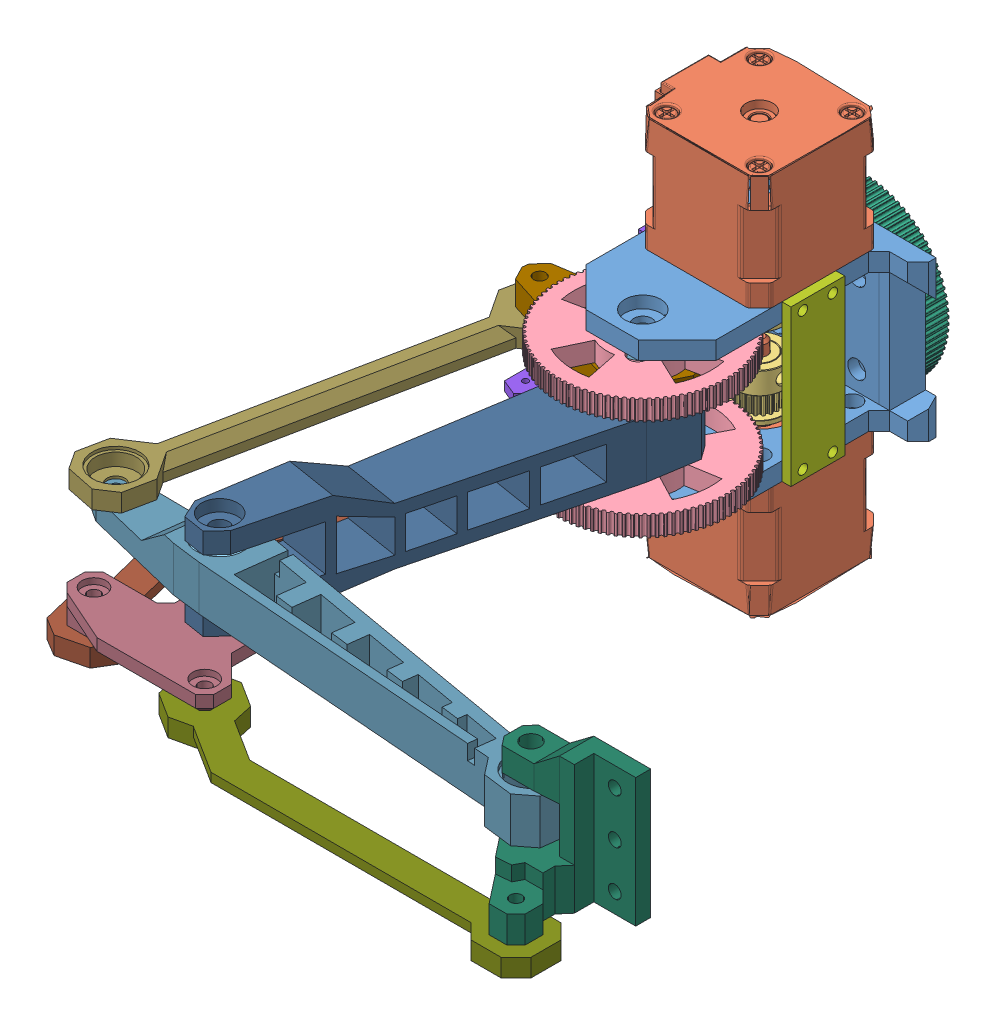
SolidWorks assembly 大臂, configuration 默认. Lengths in mm.
26 component instances, 16 part files, 62 mates.
Components (placement in the parent):
- 支架-1: 支架 [默认] at origin size (71 52.09 83.05)
- 基座电机-1: 基座电机 [默认] at (39 -47.8051 -25.5051) x (1 0 0) z (0 1 0) size (51.25 48 66.15)
- 基座电机-2: 基座电机 [默认] at (39.002 -50.2051 72.5031) x (1 0 0) z (0 -1 0) size (51.25 48 66.15)
- 基座小带轮-1: 基座小带轮 [默认] at (177.9873 -24.2051 17.4258) x (-0.72855 0 0.684993) z (0 1 0) size (16 16 16)
- 基座小带轮-2: 基座小带轮 [默认] at (36.8527 -73.8051 69.7017) x (0.998983 0 0.045086) z (0 -1 0) size (16 16 16)
- 机械臂大带轮-1: 机械臂大带轮 [默认] at (-17.6564 -0.0051 70.6178) x (0.809503 0 -0.587116) z (0.587116 0 0.809503) size (56.79 6.5 56.81)
- 机械臂大带轮轴承-1: 机械臂大带轮轴承 [默认] at (28.3216 -7.0051 156.1487) x (0.094466 0 -0.995528) z (0.995528 0 0.094466) size (15 5 15)
- 机械臂大带轮-2: 机械臂大带轮 [默认] at (140.2401 -98.0051 -48.3425) x (-0.787618 0 0.616164) z (0.616164 0 0.787618) size (56.79 6.5 56.81)
- 机械臂大带轮轴承-2: 机械臂大带轮轴承 [默认] at (217.8896 -91.5051 64.8714) x (-0.837169 0 -0.546944) z (-0.546944 0 0.837169) size (15 5 15)
- 基座大带轮-1: 基座大带轮 [默认] at (-0.0113 -0.0051 0) size (56.79 56.81 10)
- 支架横板-1: 支架横板 [默认] at origin size (3 52 18)
- 支架挡板-1: 支架挡板 [默认] at origin size (14 52 50.36)
- 大臂连杆-1: 大臂连杆 [默认] at (-14.6303 -0.0051 35.9323) x (0.945311 0 -0.32617) z (0.32617 0 0.945311) size (55.83 8 37.89)
- 大臂杆2-1: 大臂杆2 [默认] at (-17.6563 -0.0051 70.618) x (0.809502 0 -0.587118) z (0.587118 0 0.809502) size (110.73 30.5 103.66)
- 机械臂大带轮轴承-3: 机械臂大带轮轴承 [默认] at (-0.0113 -0.0051 0) size (15 5 15)
- 机械臂大带轮轴承-4: 机械臂大带轮轴承 [默认] at (217.8896 -106.0051 64.8714) x (-0.837169 0 -0.546944) z (-0.546944 0 0.837169) size (15 5 15)
- 大臂杆3-1: 大臂杆3 [默认] at (-30.4167 -0.0051 55.2903) x (0.809502 0 -0.587117) z (0.587117 0 0.809502) size (110.51 6 103.44)
- 机械臂大带轮轴承-5: 机械臂大带轮轴承 [默认] at (25.5912 -19.0051 -34.748) x (0.810265 0 0.586064) z (-0.586064 0 0.810265) size (15 5 15)
- 大臂杆1-1: 大臂杆1 [默认] at (-17.6672 -0.0051 58.6826) x (0.810062 0 -0.586344) z (0.586344 0 0.810062) size (109.93 6 102.62)
- 机械臂大带轮轴承-6: 机械臂大带轮轴承 [默认] at (-48.6211 12.4949 13.0424) x (0.985319 0 -0.170721) z (0.170721 0 0.985319) size (15 5 15)
- 三连杆-1: 三连杆 [默认] at (64.5133 -0.0051 36.3743) x (1 0 0.000008) z (-0.000008 0 1) size (57 9.5 36)
- 小臂杆2-1: 小臂杆2 [默认] at (18.7808 -0.1051 47.8224) x (0.946574 0 -0.322488) z (0.322488 0 0.946574) size (161.69 15 86.71)
- 机械臂大带轮轴承-7: 机械臂大带轮轴承 [默认] at (-23.8027 5.3949 117.6181) size (15 5 15)
- 机械臂大带轮轴承-8: 机械臂大带轮轴承 [默认] at (194.0983 -104.6051 182.4895) x (-0.837169 0 -0.546944) z (-0.546944 0 0.837169) size (15 5 15)
- 小臂连杆-1: 小臂连杆 [默认] at (75.7157 -0.0051 -1.219) x (1 0 0.000008) z (-0.000008 0 1) size (40 43 32)
- 小臂杆1-1: 小臂杆1 [默认] at (13.1016 -0.0051 53.7449) x (0.946506 0 -0.322686) z (0.322686 0 0.946506) size (129.85 6 74.64)
Mates (geometry in assembly coordinates):
- 重合1: coincident: plane of ? through (119.9887 -75.0051 -26.5) normal (0 -1 0); plane of 基座电机-1 through (99.9867 -75.0051 23.498) normal (0 1 0)
- 同心1: concentric: cylinder of ? through (115.4887 -75.0051 39) axis (0 1 0) radius 1.65; cylinder of 基座电机-1 through (115.4887 -72.5051 39) axis (0 -1 0) radius 1.25
- 平行2: parallel: plane of ? through (77.4887 -75.0051 47.75) normal (-1 0 0); plane of 基座电机-1 through (78.9867 -103.5051 29.298) normal (-1 0 0)
- 重合3: coincident: plane of ? through (119.9887 -23.0051 -26.5) normal (0 1 0); plane of 基座电机-2 through (99.9887 -23.0051 23.5) normal (0 -1 0)
- 同心4: concentric: cylinder of ? through (99.9887 -28.0051 23.5) axis (0 1 0) radius 11.5; cylinder of 基座电机-2 through (99.9887 -25.5051 23.5) axis (0 -1 0) radius 11
- 平行3: parallel: plane of ? through (77.4887 -28.0051 47.75) normal (-1 0 0); plane of 基座电机-2 through (78.9887 5.4949 17.7) normal (-1 0 0)
- 同心5: concentric: cylinder of assembly; cylinder of assembly; cylinder of 基座电机-2 through (99.9887 -25.5051 23.5) axis (0 -1 0) radius 2.5; cylinder of 基座小带轮-1 through (99.9887 -29.0051 23.5) axis (0 1 0) radius 2.5
- 重合7: coincident: plane of ? through (119.9887 -29.0051 -26.5) normal (0 -1 0); plane of 基座小带轮-1 through (99.9887 -29.0051 23.5) normal (0 -1 0)
- 同心6: concentric: cylinder of assembly; cylinder of assembly; cylinder of 基座电机-1 through (99.9867 -72.5051 23.498) axis (0 1 0) radius 2.5; cylinder of 基座小带轮-2 through (99.9867 -69.0051 23.498) axis (0 -1 0) radius 2.5
- 重合8: coincident: plane of ? through (119.9887 -69.0051 -26.5) normal (0 1 0); plane of 基座小带轮-2 through (99.9867 -69.0051 23.498) normal (0 1 0)
- 重合9: coincident: plane of ? through (119.9887 -69.0051 -26.5) normal (0 1 0); plane of 机械臂大带轮-1 through (-67.6057 -69.0051 35.8138) normal (0 -1 0)
- 同心7: concentric: cylinder of ? through (99.9887 -72.0051 62.5) axis (0 -1 0) radius 6; cylinder of 机械臂大带轮-1 through (99.9886 -66.0051 62.5002) axis (0 1 0) radius 6.85
- 重合10: coincident: plane of assembly; plane of assembly; plane of 机械臂大带轮-1 through (-67.6057 -69.0051 35.8138) normal (0 -1 0); plane of 机械臂大带轮轴承-1 through (103.6002 -69.0051 67.9044) normal (0 -1 0)
- 重合11: coincident: plane of ? through (119.9887 -29.0051 -26.5) normal (0 -1 0); plane of 机械臂大带轮-2 through (120.5631 -29.0051 -105.9538) normal (0 1 0)
- 同心9: concentric: cylinder of ? through (99.9887 -27.0051 62.5) axis (0 -1 0) radius 6; cylinder of 机械臂大带轮-2 through (99.9887 -32.0051 62.5) axis (0 -1 0) radius 6.85
- 齿轮配合1: gear = 16 : 56.7878 mm: circle of assembly; circle of assembly; circle of 机械臂大带轮-1; circle of 基座小带轮-2
- 齿轮配合2: gear = 16 : 56.7878 mm: circle of assembly; circle of assembly; circle of 机械臂大带轮-2; circle of 基座小带轮-1
- 重合13: coincident: plane of ? through (88.7387 -28.0051 -1.5) normal (0 0 -1); plane of ? through (39.3316 -20.3519 -1.5) normal (0 0 1)
- 同心11: concentric: cylinder of ? through (113.4887 -62.5051 2.5) axis (0 0 -1) radius 1.65; cylinder of ? through (113.4887 -62.5051 -7.5) axis (0 0 1) radius 1.65
- 同心12: concentric: cylinder of ? through (86.4887 -62.5051 2.5) axis (0 0 -1) radius 1.65; cylinder of ? through (86.4887 -62.5051 -7.5) axis (0 0 1) radius 1.65
- 重合14: coincident: plane of ? through (120.9887 -28.0051 47.75) normal (1 0 0); plane of ? through (120.9887 -0.0051 216) normal (-1 0 0)
- 同心13: concentric: cylinder of ? through (134.9887 -26.0051 33) axis (-1 0 0) radius 1.6; cylinder of ? through (123.9887 -26.0051 33) axis (-1 0 0) radius 1.6
- 同心14: concentric: cylinder of ? through (134.9887 -26.0051 23) axis (-1 0 0) radius 1.6; cylinder of ? through (123.9887 -26.0051 23) axis (-1 0 0) radius 1.6
- 重合15: coincident: plane of ? through (77.4887 -28.0051 47.75) normal (-1 0 0); plane of ? through (77.4887 -154.0051 -43) normal (1 0 0)
- 同心15: concentric: cylinder of ? through (73.4887 -26.0051 27) axis (1 0 0) radius 1.5; cylinder of ? through (74.4887 -26.0051 27) axis (1 0 0) radius 1.6
- 同心16: concentric: cylinder of ? through (73.4887 -26.0051 37) axis (1 0 0) radius 1.5; cylinder of ? through (74.4887 -26.0051 37) axis (1 0 0) radius 1.6
- 重合16: coincident: plane of assembly; plane of assembly; plane of 机械臂大带轮-2 through (120.5631 -35.5051 -105.9538) normal (0 -1 0); plane of 大臂连杆-1 through (-111.777 -35.5051 386.7706) normal (0 1 0)
- 同心17: concentric: cylinder of assembly; cylinder of assembly; cylinder of 机械臂大带轮-2 through (106.1503 -32.0051 70.3762) axis (0 -1 0) radius 1.6; cylinder of 大臂连杆-1 through (106.1503 -41.5051 70.3762) axis (0 1 0) radius 1.4
- 同心18: concentric: cylinder of assembly; cylinder of assembly; cylinder of 机械臂大带轮-2 through (92.1126 -32.0051 68.6616) axis (0 -1 0) radius 1.6; cylinder of 大臂连杆-1 through (92.1125 -41.5051 68.6616) axis (0 1 0) radius 1.4
- 同心21: concentric: cylinder of assembly; cylinder of assembly; cylinder of 机械臂大带轮-1 through (108.0836 -66.0051 56.6291) axis (0 1 0) radius 1.6; cylinder of 大臂杆2-1 through (108.0836 -62.5051 56.6291) axis (0 1 0) radius 1.4
- 同心22: concentric: cylinder of assembly; cylinder of assembly; cylinder of 机械臂大带轮-1 through (105.8597 -66.0051 70.5952) axis (0 1 0) radius 1.6; cylinder of 大臂杆2-1 through (105.8597 -62.5051 70.5951) axis (0 1 0) radius 1.4
- 重合19: coincident: plane of assembly; plane of assembly; plane of 机械臂大带轮-1 through (-67.6057 -62.5051 35.8138) normal (0 1 0); plane of 大臂杆2-1 through (336.7372 -62.5051 403.9768) normal (0 -1 0)
- 重合20: coincident: plane of ? through (119.9887 -75.0051 -26.5) normal (0 -1 0); plane of 大臂杆3-1 through (175.5403 -75.0051 234.1938) normal (0 1 0)
- 同心23: concentric: cylinder of ? through (69.9887 -75.0051 74.5) axis (0 1 0) radius 1.95; cylinder of 大臂杆3-1 through (69.9887 -81.0051 74.5) axis (0 1 0) radius 3
- 重合22: coincident: plane of assembly; plane of assembly; plane of 大臂连杆-1 through (-111.777 -43.5051 386.7706) normal (0 -1 0); plane of 大臂杆1-1 through (266.9222 -43.5051 -143.2537) normal (0 1 0)
- 同心25: concentric: cylinder of assembly; cylinder of assembly; cylinder of 大臂连杆-1 through (60.5809 -41.5051 57.5528) axis (0 1 0) radius 2.05; cylinder of 大臂杆1-1 through (60.5809 -42.3051 57.5528) axis (0 -1 0) radius 3
- 同心26: concentric: cylinder of assembly; cylinder of assembly; cylinder of 大臂杆1-1 through (60.5809 -48.5051 57.5528) axis (0 1 0) radius 6.85; cylinder of 机械臂大带轮轴承-6 through (60.5809 -47.7551 57.5528) axis (0 1 0) radius 6.5
- 重合23: coincident: plane of assembly; plane of assembly; plane of 大臂杆1-1 through (137.8877 -48.5051 334.9039) normal (0 -1 0); plane of 机械臂大带轮轴承-6 through (55.6608 -48.5051 63.2134) normal (0 1 0)
- 同心27: concentric: cylinder of assembly; cylinder of assembly; cylinder of 大臂杆3-1 through (69.9887 -80.0051 74.5) axis (0 1 0) radius 6.75; cylinder of 机械臂大带轮轴承-5 through (69.9887 -79.2551 74.5) axis (0 1 0) radius 6.5
- 重合24: coincident: plane of assembly; plane of assembly; plane of 大臂杆3-1 through (223.1372 -80.0051 225.9062) normal (0 -1 0); plane of 机械臂大带轮轴承-5 through (62.5011 -80.0051 74.9311) normal (0 1 0)
- 同心28: concentric: cylinder of assembly; cylinder of assembly; cylinder of 机械臂大带轮-1 through (99.9886 -66.0051 62.5002) axis (0 1 0) radius 6.85; cylinder of 机械臂大带轮轴承-1 through (99.9887 -67.2551 62.5) axis (0 1 0) radius 6.5
- 同心29: concentric: cylinder of assembly; cylinder of assembly; cylinder of 机械臂大带轮-2 through (99.9887 -32.0051 62.5) axis (0 -1 0) radius 6.85; cylinder of 机械臂大带轮轴承-2 through (99.9887 -31.2551 62.5) axis (0 -1 0) radius 6.5
- 重合25: coincident: plane of assembly; plane of assembly; plane of 机械臂大带轮-2 through (215.9078 -30.5051 -40.8816) normal (0 1 0); plane of 机械臂大带轮轴承-2 through (102.2651 -30.5051 69.6462) normal (0 -1 0)
- 同心30: concentric: cylinder of assembly; cylinder of assembly; cylinder of 大臂杆2-1 through (99.9887 -44.0051 62.5) axis (0 -1 0) radius 6.85; cylinder of 机械臂大带轮轴承-4 through (99.9887 -45.7551 62.5) axis (0 -1 0) radius 6.5
- 重合26: coincident: plane of assembly; plane of assembly; plane of 大臂杆2-1 through (336.7372 -45.0051 403.9768) normal (0 1 0); plane of 机械臂大带轮轴承-4 through (102.2651 -45.0051 69.6462) normal (0 -1 0)
- 同心31: concentric: cylinder of 大臂杆2-1 through (99.9887 -44.0051 62.5) axis (0 -1 0) radius 6.85; cylinder of ? through (99.9887 -60.2551 62.5) axis (0 1 0) radius 6.5
- 重合27: coincident: plane of 大臂杆2-1 through (336.7372 -61.0051 403.9768) normal (0 -1 0); plane of ? through (94.1744 -61.0051 67.2375) normal (0 1 0)
- 同心36: concentric: cylinder of assembly; cylinder of assembly; cylinder of 大臂杆2-1 through (76.1974 -64.0051 180.1181) axis (0 1 0) radius 3; cylinder of 三连杆-1 through (76.1974 -66.5051 180.1181) axis (0 1 0) radius 4
- 重合29: coincident: line of assembly; plane of assembly; line of 大臂杆2-1 through (70.1896 -65.5051 170.1534) axis (0.987559 0 0.157249); plane of 三连杆-1 through (-168.8043 -65.5051 390.1162) normal (0 1 0)
- 同心37: concentric: cylinder of assembly; cylinder of assembly; cylinder of 大臂杆3-1 through (46.1973 -81.0051 192.1179) axis (0 1 0) radius 3; cylinder of 三连杆-1 through (46.1973 -75.0051 192.1179) axis (0 1 0) radius 2.05
- 同心38: concentric: cylinder of assembly; cylinder of assembly; cylinder of 小臂杆2-1 through (76.1974 -57.1051 180.1181) axis (0 1 0) radius 6.85; cylinder of 机械臂大带轮轴承-7 through (76.1974 -54.8551 180.1181) axis (0 1 0) radius 6.5
- 重合30: coincident: plane of assembly; plane of assembly; plane of 小臂杆2-1 through (-257.4122 -55.6051 427.8294) normal (0 -1 0); plane of 机械臂大带轮轴承-7 through (70.3831 -55.6051 184.8556) normal (0 1 0)
- 同心39: concentric: cylinder of assembly; cylinder of assembly; cylinder of 小臂杆2-1 through (76.1974 -57.1051 180.1181) axis (0 1 0) radius 6.85; cylinder of 机械臂大带轮轴承-8 through (76.1974 -44.3551 180.1181) axis (0 -1 0) radius 6.5
- 重合31: coincident: plane of assembly; plane of assembly; plane of 小臂杆2-1 through (-257.4122 -43.6051 427.8294) normal (0 1 0); plane of 机械臂大带轮轴承-8 through (78.4737 -43.6051 187.2643) normal (0 -1 0)
- 同心40: concentric: cylinder of assembly; cylinder of assembly; cylinder of 大臂杆2-1 through (76.1974 -64.0051 180.1181) axis (0 1 0) radius 3; cylinder of 机械臂大带轮轴承-7 through (76.1974 -54.8551 180.1181) axis (0 1 0) radius 3
- 重合32: coincident: plane of assembly; plane of assembly; plane of 大臂杆2-1 through (336.7372 -57.1051 403.9768) normal (0 1 0); plane of 小臂杆2-1 through (-53.2143 -57.1051 566.9677) normal (0 -1 0)
- 同心41: concentric: cylinder of assembly; cylinder of assembly; cylinder of 大臂杆1-1 through (36.5116 -47.5051 175.1141) axis (0 -1 0) radius 3; cylinder of 小臂杆2-1 through (36.5116 -57.1051 175.1141) axis (0 1 0) radius 2.05
- 同心43: concentric: cylinder of assembly; cylinder of assembly; cylinder of 三连杆-1 through (91.1972 -71.5051 200.1182) axis (0 1 0) radius 2.05; cylinder of 小臂杆1-1 through (91.1972 -77.5051 200.1182) axis (0 1 0) radius 3
- 重合34: coincident: plane of assembly; plane of assembly; plane of 三连杆-1 through (-168.8043 -71.5051 390.1162) normal (0 -1 0); plane of 小臂杆1-1 through (92.6261 -71.5051 64.111) normal (0 1 0)
- 同心44: concentric: cylinder of assembly; cylinder of assembly; cylinder of 小臂连杆-1 through (210.2545 -58.0051 215.1303) axis (0 -1 0) radius 2.05; cylinder of 小臂杆1-1 through (210.2545 -77.5051 215.1303) axis (0 1 0) radius 3
- 同心45: concentric: cylinder of assembly; cylinder of assembly; cylinder of 小臂杆2-1 through (195.2547 -57.1051 195.1302) axis (0 1 0) radius 6.85; cylinder of 小臂连杆-1 through (195.2547 -58.0051 195.1302) axis (0 -1 0) radius 3.15
- 重合35: coincident: plane of assembly; plane of assembly; plane of 小臂杆2-1 through (-53.2143 -57.1051 566.9677) normal (0 -1 0); plane of 小臂连杆-1 through (-194.7468 -57.1051 375.1271) normal (0 1 0)
